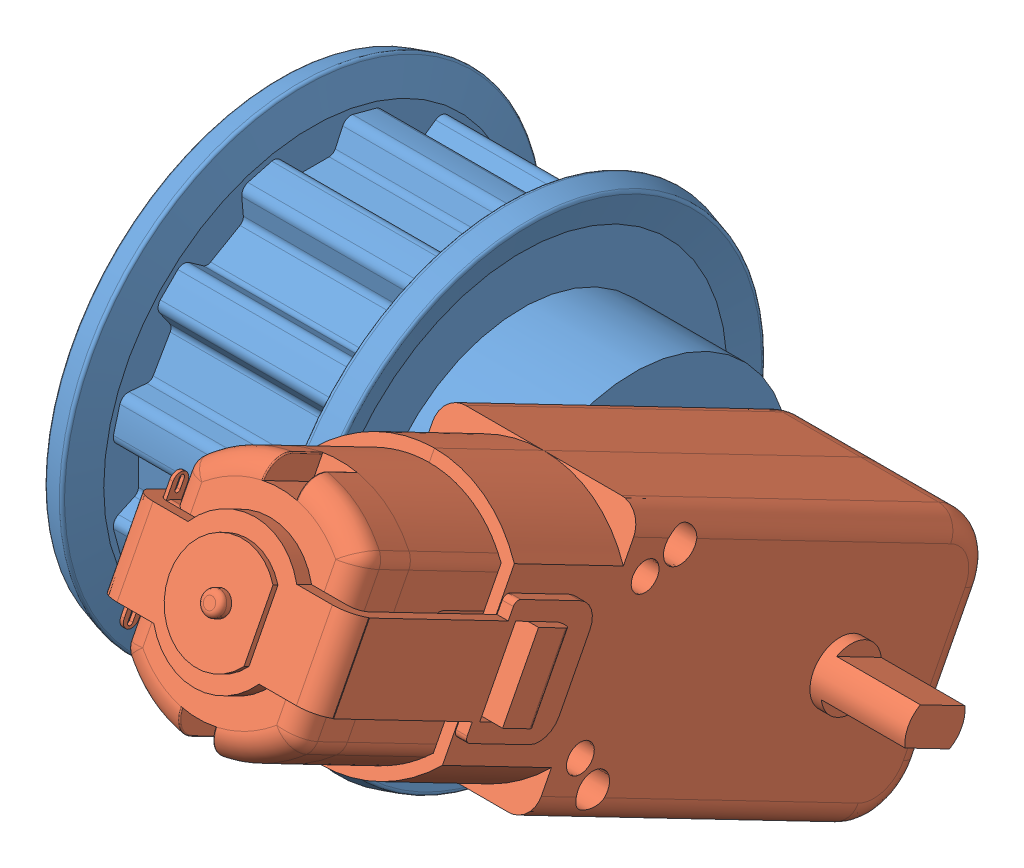
SolidWorks assembly TimingPulley, configuration Default. Lengths in mm.
Overall size (58.72 55.94 74.13).
2 component instances, 2 part files, 2 mates.
Components (placement in the parent):
- PulleyMotor-1: PulleyMotor [Domyślna] at (26.2304 37.7809 -31.1401) size (31.72 43.13 43.13)
- Motor DC-1: Motor DC [Default] at (68.3863 73.6203 -22.463) x (0 0.460062 0.887887) z (-1 0 0) size (70 22 34.5)
Mates (geometry in assembly coordinates):
- Coincident1: coincident anti-aligned: plane of T10 belt 12 teeth pulley with guides-1 through (26.2304 40.7809 -31.1401) normal (1 0 0); plane of Motor DC-1 through (26.2304 39.4408 -32.0002) normal (-1 0 0)
- Concentric1: concentric: cylinder of T10 belt 12 teeth pulley with guides-1 through (26.2304 37.7809 -31.1401) axis (1 0 0) radius 3; cylinder of Motor DC-1 through (28.2304 37.7809 -31.1401) axis (1 0 0) radius 2.7
